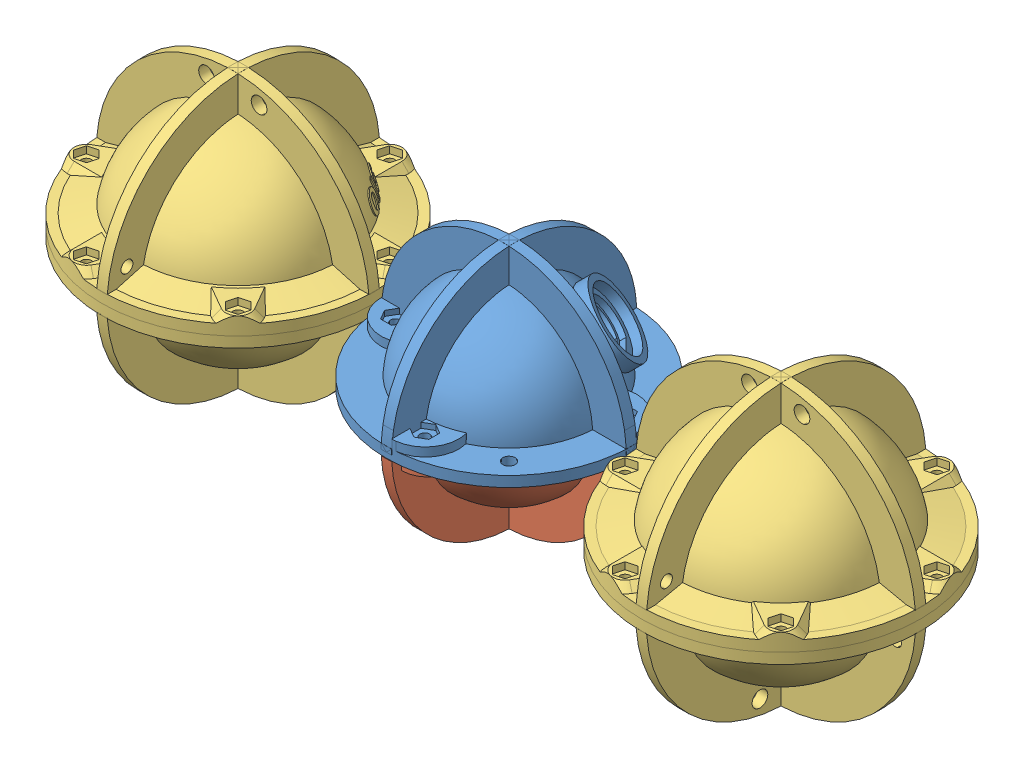
SolidWorks assembly Housing_comparison, configuration Default. Lengths in mm.
Overall size (233.69 79.92 79.7).
8 component instances, 4 part files, 14 mates.
Components (placement in the parent):
- Housing2_Boss-1: Housing2_Boss [2-230 O-ring] at origin size (89 44.86 89) (hidden)
- Housing2_Boss-2: Housing2_Boss [Housing TOP] x (-1 0 0) z (0 0 1) size (89 48.86 89) (hidden)
- enclosure_half_one-1: enclosure_half_one [Default] at (-80.4868 0 0) x (-1 0 0) z (0 0 -1) size (70 36.5 70)
- enclosure_half_two-1: enclosure_half_two [Default] at (-80.4868 0 0) x (1 0 0) z (0 0 -1) size (69.92 35 69.92)
- housing2_rev2-1: housing2_rev2 [2-140] at (-157.834 0 0) x (0 0 1) z (-1 0 0) size (77.69 38.96 77.69)
- housing2_rev2-2: housing2_rev2 [2-140_UP] at (-157.834 0 0) x (1 0 0) z (0 0 -1) size (77.69 40.96 77.69)
- housing2_rev2-5: housing2_rev2 [2-140_BIG] at (-2.834 0 0) x (0 0 1) z (-1 0 0) size (79.7 39.96 79.7)
- housing2_rev2-6: housing2_rev2 [2-140_UP_BIG'] at (-2.834 0 0) x (1 0 0) z (0 0 -1) size (79.7 41.96 79.7)
Mates (geometry in assembly coordinates):
- Coincident1: coordinate: point of Housing2_Boss-1
- Coincident3: coincident: unknown of Housing2_Boss-2
- Coincident5: coincident aligned: plane of Housing2_Boss-2 through (0 0 0) normal (0 0 1)
- Coincident6: coincident anti-aligned: plane of Housing2_Boss-2 through (0 0 0) normal (-1 0 0)
- Coincident11: coincident: point of enclosure_half_one-1; point of enclosure_half_two-1
- Coincident14: coincident anti-aligned: plane of enclosure_half_one-1 through (-80.4868 0 0) normal (0 1 0); plane of enclosure_half_two-1 through (-80.4868 0 0) normal (0 -1 0)
- Coincident15: coincident anti-aligned: plane of enclosure_half_one-1 through (-80.4868 0 0) normal (-1 0 0); plane of enclosure_half_two-1 through (-80.4868 0 0) normal (1 0 0)
- Coincident16: coincident aligned: plane of enclosure_half_one-1 through (-80.4868 0 0) normal (0 1 0)
- Coincident18: coincident aligned: plane of housing2_rev2-1 through (-157.834 0 0) normal (0 1 0)
- Coincident21: coincident: point of housing2_rev2-1; point of housing2_rev2-2
- Coincident22: coincident anti-aligned: plane of housing2_rev2-1 through (-157.834 0 0) normal (0 1 0); plane of housing2_rev2-2 through (-157.834 0 0) normal (0 -1 0)
- Coincident24: coincident anti-aligned: plane of enclosure_half_one-1 through (-80.4868 0 0) normal (0 0 -1)
- Coincident25: coincident aligned: plane of housing2_rev2-1 through (-157.834 0 0) normal (0 0 1)
- Coincident26: coincident anti-aligned: plane of housing2_rev2-1 through (-157.834 0 0) normal (-1 0 0); plane of housing2_rev2-2 through (-157.834 0 0) normal (1 0 0)
